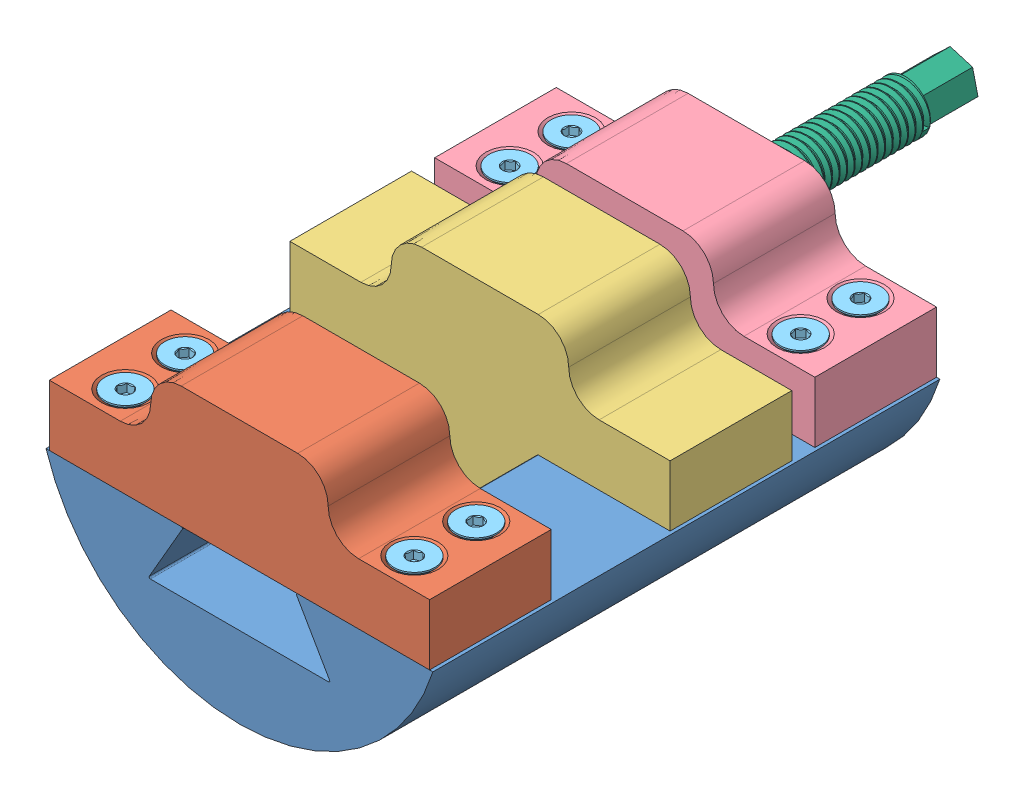
SolidWorks assembly clamp-assy, configuration Default. Lengths in mm.
Overall size (76.32 52 141.33).
13 component instances, 6 part files, 26 mates.
Components (placement in the parent):
- clamp-base-1: clamp-base [Default] at (-9.8185 32.8244 -74.4553) size (76.32 28 100)
- clamp-back-face-1: clamp-back-face [Default] at (-9.8185 32.8244 25.5447) x (0 0 -1) z (1 0 0) size (24 24 75)
- clamp-front-face-1: clamp-front-face [Default] at (-9.8185 32.8244 -21.9008) x (0 0 -1) z (1 0 0) size (24 36 75)
- clamp-screw-holder-1: clamp-screw-holder [Default] at (-9.8185 32.8244 -74.4553) x (0 0 1) z (-1 0 0) size (24 24 75)
- M4-18-flathead-1: M4-18-flathead [93395A261] at (-38.3185 32.8244 -68.4553) x (1 0 0) z (0 1 0) size (8 8 18.43)
- M4-18-flathead-2: M4-18-flathead [93395A261] at (-38.521 32.8244 -56.4553) x (0.982082 0 -0.188455) z (0 1 0) size (8 8 18.43)
- M4-18-flathead-6: M4-18-flathead [93395A261] at (-38.521 32.8244 7.5447) x (0.918365 0 -0.395734) z (0 1 0) size (8 8 18.43)
- M4-18-flathead-8: M4-18-flathead [93395A261] at (-38.3185 32.8244 19.5447) x (0.8 0 -0.6) z (0 1 0) size (8 8 18.43)
- M4-18-flathead-10: M4-18-flathead [93395A261] at (18.6815 32.8244 19.5447) x (0.63358 0 -0.773678) z (0 1 0) size (8 8 18.43)
- M4-18-flathead-12: M4-18-flathead [93395A261] at (18.884 32.8244 7.5447) x (0.443629 0 -0.896211) z (0 1 0) size (8 8 18.43)
- M4-18-flathead-14: M4-18-flathead [93395A261] at (18.884 32.8244 -56.4553) x (0.263225 0 -0.964735) z (0 1 0) size (8 8 18.43)
- M4-18-flathead-16: M4-18-flathead [93395A261] at (18.6815 32.8244 -68.4553) x (0.120178 0 -0.992752) z (0 1 0) size (8 8 18.43)
- screw-2: screw [Default] at (-9.8185 32.8244 -115.7836) x (0.96201 -0.273015 0) z (0 0 1) size (10.08 10.11 80)
Mates (geometry in assembly coordinates):
- Coincident1: coincident anti-aligned: plane of clamp-base-1 through (-47.976 20.8244 25.5447) normal (0 1 0); plane of clamp-back-face-1 through (-47.3185 20.8244 1.5447) normal (0 -1 0)
- Coincident2: coincident aligned: plane of clamp-base-1 through (-9.8185 32.8244 25.5447) normal (0 0 1); plane of clamp-back-face-1 through (-9.8185 32.8244 25.5447) normal (0 0 1)
- Coincident6: coincident anti-aligned: plane of clamp-base-1 through (8.1815 8.8244 25.5447) normal (0 1 0); plane of clamp-front-face-1 through (8.1815 8.8244 16.0465) normal (0 -1 0)
- Coincident8: coincident anti-aligned: plane of clamp-base-1 through (-27.8185 8.8244 25.5447) normal (0.866025 -0.5 0); plane of clamp-front-face-1 through (-27.8185 8.8244 16.0465) normal (-0.866025 0.5 0)
- Coincident9: coincident aligned: plane of clamp-back-face-1 through (27.6815 44.8244 1.5447) normal (1 0 0); plane of clamp-front-face-1 through (27.6815 44.8244 -45.9008) normal (1 0 0)
- Coincident10: coincident aligned: plane of clamp-front-face-1 through (27.6815 44.8244 -45.9008) normal (1 0 0); plane of clamp-screw-holder-1 through (27.6815 44.8244 -50.4553) normal (1 0 0)
- Coincident11: coincident anti-aligned: plane of clamp-base-1 through (-47.976 20.8244 25.5447) normal (0 1 0); plane of clamp-screw-holder-1 through (27.6815 20.8244 -50.4553) normal (0 -1 0)
- Coincident12: coincident aligned: plane of clamp-base-1 through (-9.8185 32.8244 -74.4553) normal (0 0 -1); plane of clamp-screw-holder-1 through (-9.8185 32.8244 -74.4553) normal (0 0 -1)
- Concentric1: concentric anti-aligned: cylinder of clamp-screw-holder-1 through (-38.3185 32.8244 -68.4553) axis (0 1 0) radius 2.25; cone of M4-18-flathead-1 through (-38.3185 30.5244 -68.4553) axis (0 -1 0)
- Coincident13: coincident aligned: plane of clamp-screw-holder-1 through (-47.3185 32.8244 -74.4553) normal (0 1 0); plane of M4-18-flathead-1 through (-38.3185 32.8244 -66.4553) normal (0 1 0)
- Concentric2: concentric anti-aligned: cylinder of clamp-screw-holder-1 through (-38.521 32.8244 -56.4553) axis (0 1 0) radius 2.25; cone of M4-18-flathead-2 through (-38.521 30.5244 -56.4553) axis (0 -1 0)
- Coincident14: coincident aligned: plane of clamp-screw-holder-1 through (-47.3185 32.8244 -74.4553) normal (0 1 0); plane of M4-18-flathead-2 through (-38.144 32.8244 -54.4912) normal (0 1 0)
- Concentric5: concentric anti-aligned: cylinder of clamp-back-face-1 through (-38.521 32.8244 7.5447) axis (0 1 0) radius 2.25; cone of M4-18-flathead-6 through (-38.521 30.5244 7.5447) axis (0 -1 0)
- Coincident17: coincident aligned: plane of clamp-back-face-1 through (-47.3185 32.8244 25.5447) normal (0 1 0); plane of M4-18-flathead-6 through (-37.7295 32.8244 9.3814) normal (0 1 0)
- Concentric6: concentric anti-aligned: cylinder of clamp-back-face-1 through (-38.3185 32.8244 19.5447) axis (0 1 0) radius 2.25; cone of M4-18-flathead-8 through (-38.3185 30.5244 19.5447) axis (0 -1 0)
- Coincident18: coincident aligned: plane of clamp-back-face-1 through (-47.3185 32.8244 25.5447) normal (0 1 0); plane of M4-18-flathead-8 through (-37.1185 32.8244 21.1447) normal (0 1 0)
- Concentric7: concentric anti-aligned: cylinder of clamp-back-face-1 through (18.6815 32.8244 19.5447) axis (0 1 0) radius 2.25; cone of M4-18-flathead-10 through (18.6815 30.5244 19.5447) axis (0 -1 0)
- Coincident19: coincident aligned: plane of clamp-back-face-1 through (27.6815 32.8244 25.5447) normal (0 1 0); plane of M4-18-flathead-10 through (20.2289 32.8244 20.8118) normal (0 1 0)
- Concentric8: concentric anti-aligned: cylinder of clamp-back-face-1 through (18.884 32.8244 7.5447) axis (0 1 0) radius 2.25; cone of M4-18-flathead-12 through (18.884 30.5244 7.5447) axis (0 -1 0)
- Coincident20: coincident aligned: plane of clamp-back-face-1 through (27.6815 32.8244 25.5447) normal (0 1 0); plane of M4-18-flathead-12 through (20.6764 32.8244 8.4319) normal (0 1 0)
- Concentric9: concentric anti-aligned: cylinder of clamp-screw-holder-1 through (18.884 32.8244 -56.4553) axis (0 1 0) radius 2.25; cone of M4-18-flathead-14 through (18.884 30.5244 -56.4553) axis (0 -1 0)
- Coincident21: coincident aligned: plane of clamp-screw-holder-1 through (27.6815 32.8244 -74.4553) normal (0 1 0); plane of M4-18-flathead-14 through (20.8135 32.8244 -55.9289) normal (0 1 0)
- Concentric10: concentric anti-aligned: cylinder of clamp-screw-holder-1 through (18.6815 32.8244 -68.4553) axis (0 1 0) radius 2.25; cone of M4-18-flathead-16 through (18.6815 30.5244 -68.4553) axis (0 -1 0)
- Coincident22: coincident aligned: plane of clamp-screw-holder-1 through (27.6815 32.8244 -74.4553) normal (0 1 0); plane of M4-18-flathead-16 through (20.667 32.8244 -68.215) normal (0 1 0)
- Concentric13: concentric anti-aligned: cylinder of screw-2 through (-9.8185 32.8244 -45.7836) axis (0 0 1) radius 4; cylinder of clamp-front-face-1 through (-9.8185 32.8244 -45.9008) axis (0 0 -1) radius 4
- Lock3: lock: unknown of clamp-front-face-1; unknown of screw-2
